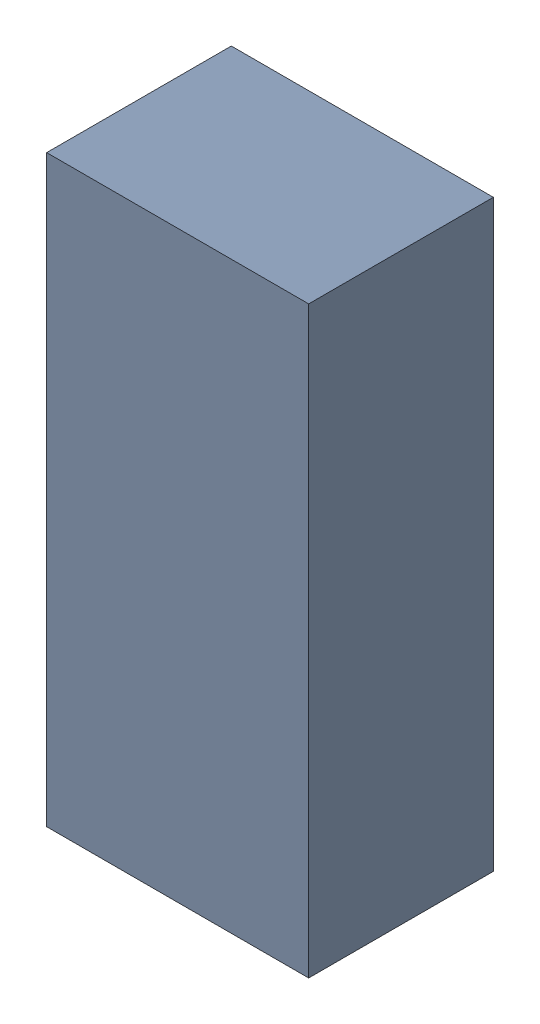
SolidWorks assembly D1, configuration Default. Lengths in mm.
Overall size (1.84 4.1 1.3).
2 component instances, 1 part files, 0 mates.
Components (placement in the parent):
- 710423184-1: 710423184 [Default] at (37.0701 4.4001 -1.9115) size (1.84 4.1 1.3)
  - Extruded (29)-1: Extruded (29) [Default] at origin size (1.84 4.1 1.3)
